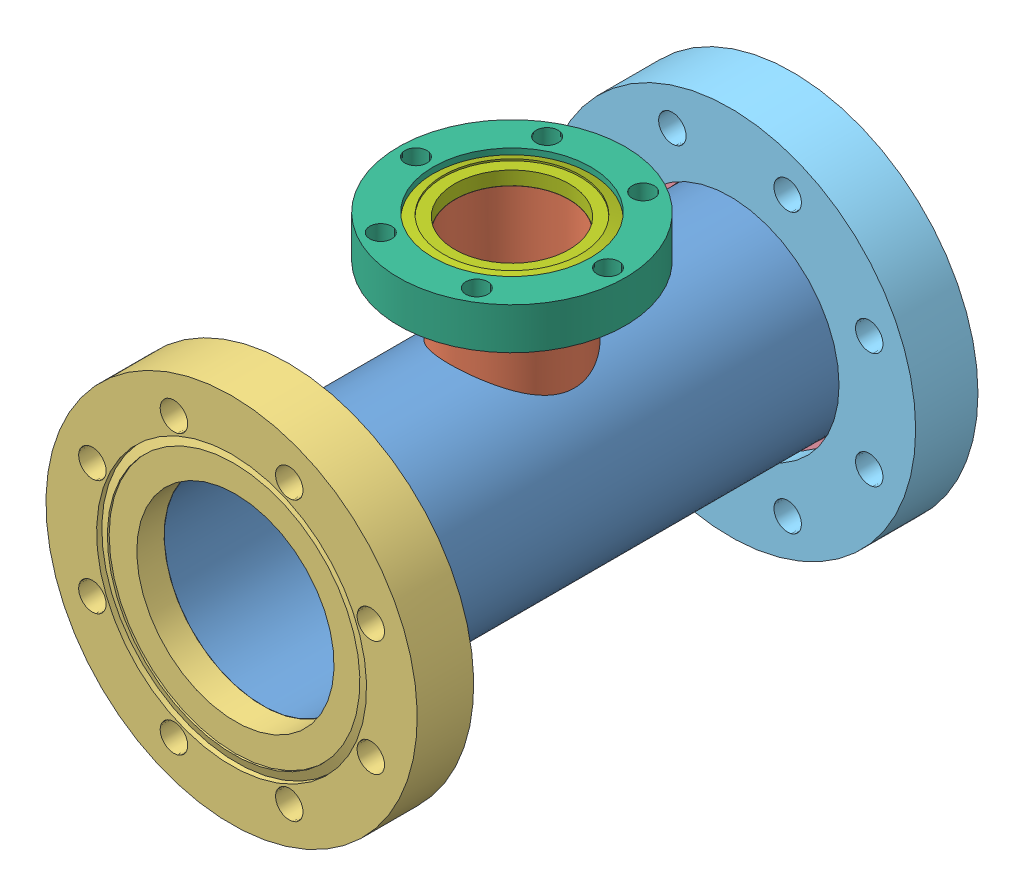
SolidWorks assembly 404048, configuration Default. Lengths in mm.
Overall size (113.54 119.23 171.45).
9 component instances, 7 part files, 0 mates.
Components (placement in the parent):
- 404048-001-1: 404048-001 [Default] at origin size (63.5 63.5 152.4)
- 404048-002-1: 404048-002 [Default] at (0 0 76.2) x (1 0 0) z (0 1 0) size (38.1 38.1 35.24)
- 110021 (4.5 X 2.5 NR)_1-1: 110021 (4.5 X 2.5 NR)_1 [Default] at (0 0 161.925) x (0 0 -1) z (1 0 0) size (17.27 113.54 113.54)
- 100021 (4.5 X 2.5 R)-1: 100021 (4.5 X 2.5 R) [Default] at (0 0 3.175) x (0 0 -1) z (1 0 0) size (19.05 113.54 113.54)
  - 100021 (4.5 X 2.5 INS)-1: 100021 (4.5 X 2.5 INS) [Default] at origin size (12.04 82.3 82.3)
  - 100021 (4.5 X 2.5 REC)-1: 100021 (4.5 X 2.5 REC) [Default] at (-6.35 0 0) x (1 0 0) z (0 0 -1) size (19.05 113.54 113.54)
- 100014 (2.75 X 1.5 R)_2-1: 100014 (2.75 X 1.5 R)_2 [Default] at (0 62.4586 76.2) x (0 -1 0) z (1 0 0) size (12.7 69.34 69.34)
  - 100014 (2.75 X 1.5 REC)_3-1: 100014 (2.75 X 1.5 REC)_3 [Default] at origin size (12.7 69.34 69.34)
  - 100014 (2.75 X 1.5 INS)_2-1: 100014 (2.75 X 1.5 INS)_2 [Default] at (1.17 0 0) x (1 0 0) z (0 0.994423 -0.105464) size (6.96 48.1 48.1)
